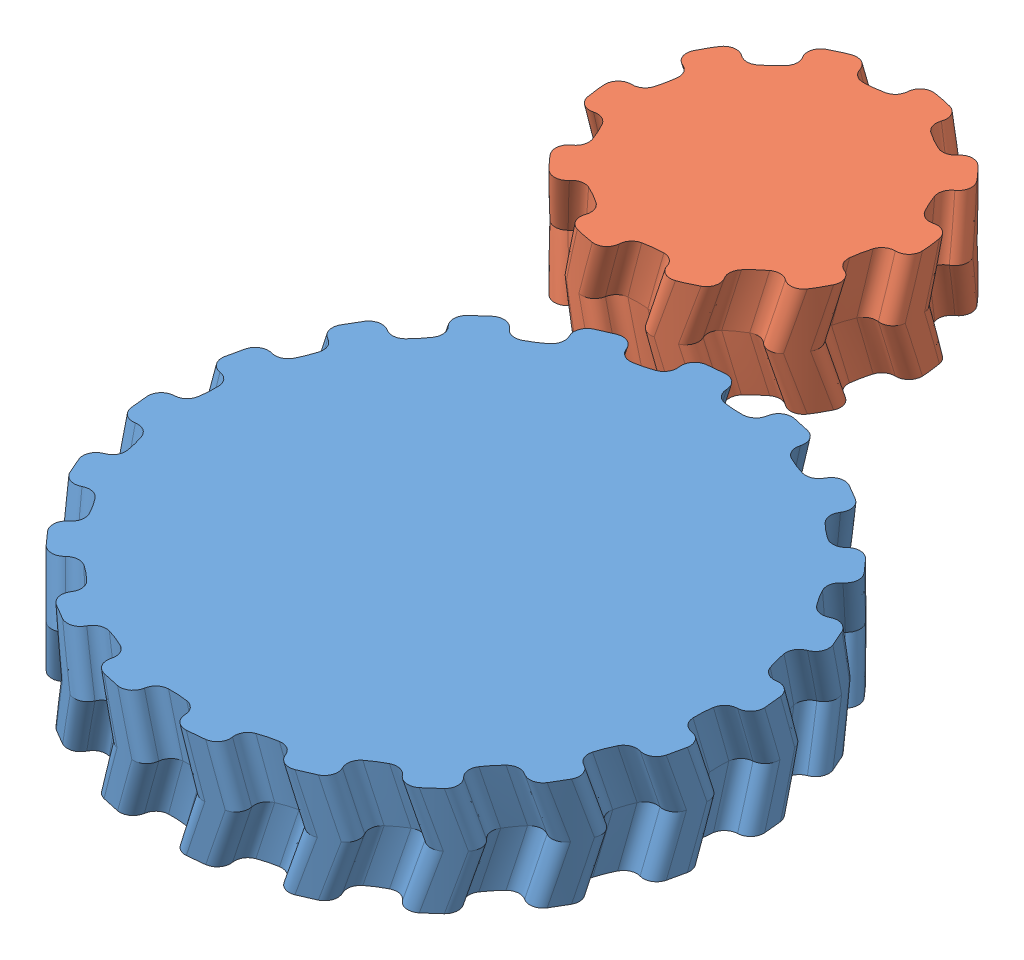
SolidWorks assembly Gear_Test_Assembly, configuration Default. Lengths in mm.
Overall size (57.22 10 85.52).
2 component instances, 2 part files, 1 mates.
Components (placement in the parent):
- Arm_Gear-1: Arm_Gear [Default] at (0 -31.8563 0) size (53.43 10 53.43)
- Nema_Gear-2: Nema_Gear [Default] at (-16.4963 -31.8563 -44.8516) x (-1 0 0) z (0 0 1) size (28.01 10 27.91)
Mates (geometry in assembly coordinates):
- Coincident7: coincident: plane of Arm_Gear-1 through (0 -26.8563 0) normal (0 1 0); plane of Nema_Gear-2 through (-16.4963 -26.8563 -44.8516) normal (0 1 0)
